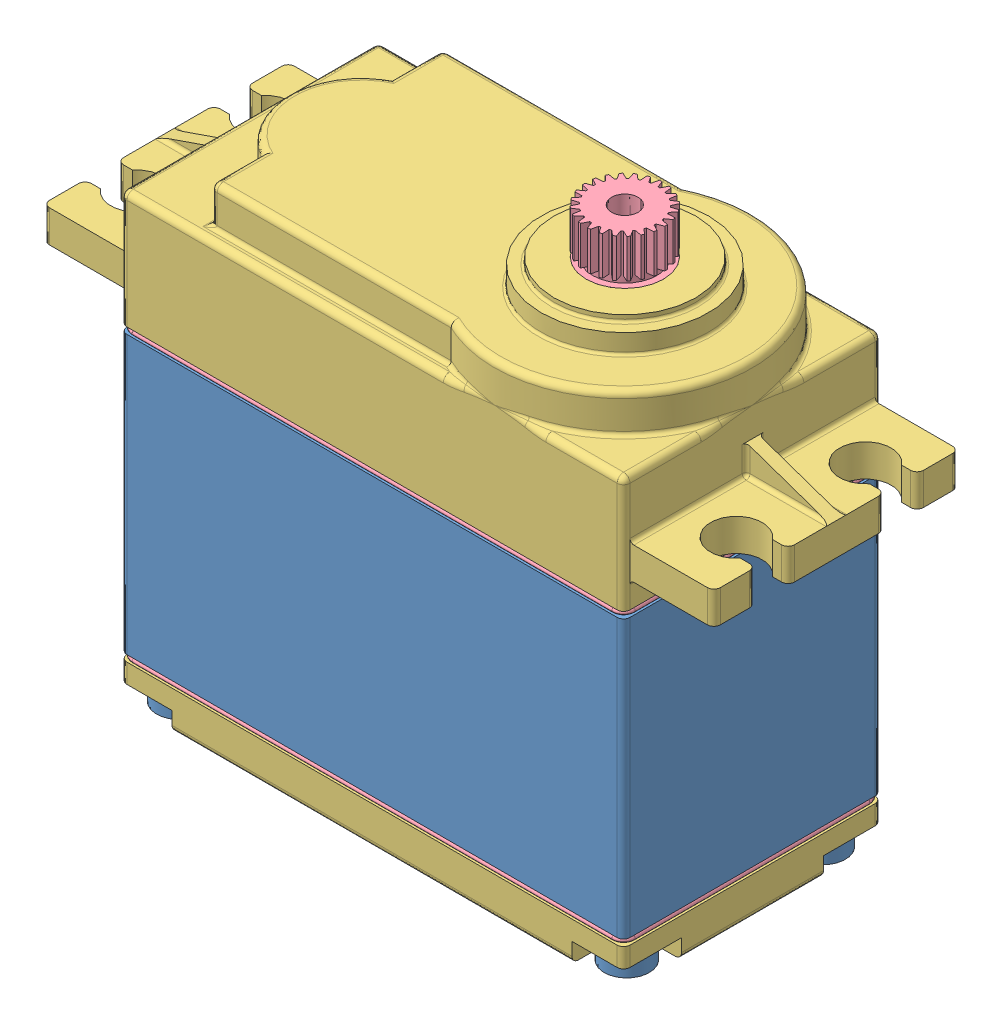
SolidWorks assembly РМ, configuration По умолчанию. Lengths in mm.
Overall size (52 43 23.81).
64 component instances, 28 part files, 82 mates.
Components (placement in the parent):
- Корпус-2: Корпус [По умолчанию] at origin size (39 28 20)
- Плата-1: Плата [По умолчанию] at (0 -10.5 0) x (-1 0 0) z (0 0 -1) size (37.4 1 18.4)
- Крышка-1: Крышка [По умолчанию] at (0 -13 0) x (-1 0 0) z (0 0 1) size (39 4 20)
- G1-1: G1 [Spur01] at (9.6 15.75 0) x (0.004766 0 0.999989) z (0 1 0) size (17.19 17.2 15.5)
- G2-1: G2 [Spur02] at (-1.2 16.75 0) x (-0.940242 0 0.340506) z (0 1 0) size (5.94 5.98 7)
- G3-1: G3 [G3] at (-1.2 19.25 0) x (0.340506 0 0.940242) z (0 1 0) size (13.18 13.2 2)
- G4-1: G4 [G4] at (-9.9 18.5 0) x (-0.495475 0 0.868622) z (0 -1 0) size (5.33 5.33 4)
- G5-1: G5 [G6] at (-9.9 12.5 0) x (0.495475 0 -0.868622) z (0 1 0) size (14.38 14.4 5.5)
- G6-1: G6 [G5] at (-1.2 12 0) x (0.105267 0 -0.994444) z (0 -1 0) size (4.1 4.1 2.5)
- G7-1: G7 [G7] at (-1.2 11.25 0) x (0.994444 0 0.105267) z (0 -1 0) size (14.99 15 1)
- G8-1: G8 [П8] at (-9.7 11.25 0) x (0.946769 0 0.321915) z (0 -1 0) size (2.9 3 1)
- Пласт2-1: Пласт2 [По умолчанию] at (9.6 16.5 0) x (0.004766 0 0.999989) z (0.999989 0 -0.004766) size (10 3.05 9.77)
- Пласт1-1: Пласт1 [По умолчанию] at (9.6 14.5 0) x (-0.004766 0 -0.999989) z (0.999989 0 -0.004766) size (7 1.5 9.77)
- Ось-1: Ось [По умолчанию] at (-1.2 15.75 0) x (0.961755 0 0.273911) z (0.273911 0 -0.961755) size (1.5 12.5 1.5)
- Ось1-1: Ось1 [По умолчанию] at (-9.9 18.75 0) x (0.831133 0 0.556074) z (-0.556074 0 0.831133) size (1.5 6.5 1.5)
- Подшипник_1-1: Подшипник_1 [По умолчанию] at (9.6 13.5 0) size (14.01 2 14.01)
  - Вн_кольцо-1: Вн_кольцо [По умолчанию] at origin size (7 2 7)
  - Нар_кольцо-2: Нар_кольцо [По умолчанию] x (0.605705 0 -0.795689) z (0.795689 0 0.605705) size (10 2 10)
  - Шарик-1: Шарик [По умолчанию] at (-3.9953 0 0.1946) size (1.5 1.5 1.5)
  - Шарик-2: Шарик [По умолчанию] at (-3.3466 0 -2.1909) x (0.809017 0 0.587785) z (-0.587785 0 0.809017) size (1.5 1.5 1.5)
  - Шарик-3: Шарик [По умолчанию] at (-1.4197 0 -3.7396) x (0.309017 0 0.951057) z (-0.951057 0 0.309017) size (1.5 1.5 1.5)
  - Шарик-4: Шарик [По умолчанию] at (1.0495 0 -3.8599) x (-0.309017 0 0.951057) z (-0.951057 0 -0.309017) size (1.5 1.5 1.5)
  - Шарик-5: Шарик [По умолчанию] at (3.1179 0 -2.5058) x (-0.809017 0 0.587785) z (-0.587785 0 -0.809017) size (1.5 1.5 1.5)
  - Шарик-6: Шарик [По умолчанию] at (3.9953 0 -0.1946) x (-1 0 0) z (0 0 -1) size (1.5 1.5 1.5)
  - Шарик-7: Шарик [По умолчанию] at (3.3466 0 2.1909) x (-0.809017 0 -0.587785) z (0.587785 0 -0.809017) size (1.5 1.5 1.5)
  - Шарик-8: Шарик [По умолчанию] at (1.4197 0 3.7396) x (-0.309017 0 -0.951057) z (0.951057 0 -0.309017) size (1.5 1.5 1.5)
  - Шарик-9: Шарик [По умолчанию] at (-1.0495 0 3.8599) x (0.309017 0 -0.951057) z (0.951057 0 0.309017) size (1.5 1.5 1.5)
  - Шарик-10: Шарик [По умолчанию] at (-3.1179 0 2.5058) x (0.809017 0 -0.587785) z (0.587785 0 0.809017) size (1.5 1.5 1.5)
- Винт-1: Винт [По умолчанию] at (17.35 0.5 7.6) x (0.946284 0 0.323336) z (0.323336 0 -0.946284) size (3.5 31 3.5)
- Упл_кольцо-1: Упл_кольцо [По умолчанию] at (17.35 -13.5 7.6) x (0.852696 0 0.522408) z (-0.522408 0 0.852696) size (3.2 0.5 3.2)
- Винт-2: Винт [По умолчанию] at (17.35 0 -7.6) x (0.966388 0 0.257088) z (0.257088 0 -0.966388) size (3.5 31 3.5) (suppressed, hidden)
- Упл_кольцо-2: Упл_кольцо [По умолчанию] at (17.35 -14 -7.6) size (3.2 0.5 3.2) (suppressed, hidden)
- Винт-3: Винт [По умолчанию] at (-17.35 0 -7.6) x (-0.966388 0 0.257088) z (0.257088 0 0.966388) size (3.5 31 3.5) (suppressed, hidden)
- Упл_кольцо-3: Упл_кольцо [По умолчанию] at (-17.35 -14 -7.6) x (-1 0 0) z (0 0 -1) size (3.2 0.5 3.2) (suppressed, hidden)
- Упл_кольцо-4: Упл_кольцо [По умолчанию] at (-17.35 -14 7.6) x (-1 0 0) z (0 0 -1) size (3.2 0.5 3.2) (suppressed, hidden)
- Винт-4: Винт [По умолчанию] at (-17.35 0 7.6) x (-0.966388 0 -0.257088) z (-0.257088 0 0.966388) size (3.5 31 3.5) (suppressed, hidden)
- Основание-1: Основание [По умолчанию] at (0 15 0) x (-1 0 0) z (0 0 -1) size (52 14 20.07)
- Подшипник_1-2: Подшипник_1 [По умолчанию] at (9.6 22 0) size (14.01 2 14.01)
  - Вн_кольцо-1: Вн_кольцо [По умолчанию] at origin size (7 2 7)
  - Нар_кольцо-2: Нар_кольцо [По умолчанию] x (0.605705 0 -0.795689) z (0.795689 0 0.605705) size (10 2 10)
  - Шарик-1: Шарик [По умолчанию] at (-3.9953 0 0.1946) size (1.5 1.5 1.5)
  - Шарик-2: Шарик [По умолчанию] at (-3.3466 0 -2.1909) x (0.809017 0 0.587785) z (-0.587785 0 0.809017) size (1.5 1.5 1.5)
  - Шарик-3: Шарик [По умолчанию] at (-1.4197 0 -3.7396) x (0.309017 0 0.951057) z (-0.951057 0 0.309017) size (1.5 1.5 1.5)
  - Шарик-4: Шарик [По умолчанию] at (1.0495 0 -3.8599) x (-0.309017 0 0.951057) z (-0.951057 0 -0.309017) size (1.5 1.5 1.5)
  - Шарик-5: Шарик [По умолчанию] at (3.1179 0 -2.5058) x (-0.809017 0 0.587785) z (-0.587785 0 -0.809017) size (1.5 1.5 1.5)
  - Шарик-6: Шарик [По умолчанию] at (3.9953 0 -0.1946) x (-1 0 0) z (0 0 -1) size (1.5 1.5 1.5)
  - Шарик-7: Шарик [По умолчанию] at (3.3466 0 2.1909) x (-0.809017 0 -0.587785) z (0.587785 0 -0.809017) size (1.5 1.5 1.5)
  - Шарик-8: Шарик [По умолчанию] at (1.4197 0 3.7396) x (-0.309017 0 -0.951057) z (0.951057 0 -0.309017) size (1.5 1.5 1.5)
  - Шарик-9: Шарик [По умолчанию] at (-1.0495 0 3.8599) x (0.309017 0 -0.951057) z (0.951057 0 0.309017) size (1.5 1.5 1.5)
  - Шарик-10: Шарик [По умолчанию] at (-3.1179 0 2.5058) x (0.809017 0 -0.587785) z (0.587785 0 0.809017) size (1.5 1.5 1.5)
- Прокл-1: Прокл [По умолчанию] at (0 -11.75 0) x (1 0 0) z (0 0 1) size (39 0.5 20)
- Прокл-2: Прокл [По умолчанию] at (0 10.25 0) size (39 0.5 20)
- Винт-8: Винт [По умолчанию] at (17.35 0.5 -7.6) x (0.946284 0 0.323336) z (0.323336 0 -0.946284) size (3.5 31 3.5)
- Упл_кольцо-5: Упл_кольцо [По умолчанию] at (17.35 -13.5 -7.6) x (0.852696 0 0.522408) z (-0.522408 0 0.852696) size (3.2 0.5 3.2)
- Винт-9: Винт [По умолчанию] at (-17.35 0.5 7.6) x (0.946284 0 0.323336) z (0.323336 0 -0.946284) size (3.5 31 3.5)
- Упл_кольцо-6: Упл_кольцо [По умолчанию] at (-17.35 -13.5 7.6) x (0.852696 0 0.522408) z (-0.522408 0 0.852696) size (3.2 0.5 3.2)
- Винт-10: Винт [По умолчанию] at (-17.35 0.5 -7.6) x (0.946284 0 0.323336) z (0.323336 0 -0.946284) size (3.5 31 3.5)
- Упл_кольцо-7: Упл_кольцо [По умолчанию] at (-17.35 -13.5 -7.6) x (0.852696 0 0.522408) z (-0.522408 0 0.852696) size (3.2 0.5 3.2)
- Штырь-1: Штырь [По умолчанию] at (16.0999 17 -0.031) x (-0.26515 0 -0.964207) z (0.964207 0 -0.26515) size (2 7 2)
- Дв_корп-1: Дв_корп [По умолчанию] at (-9.7 0 0) size (17.2 18 17.2)
- Дв_вал-1: Дв_вал [По умолчанию] at (-9.7 7 0) size (1 10 1)
- Дв_крышка-1: Дв_крышка [По умолчанию] at (-9.7 -9.5 0) x (-0.837169 0 -0.546944) z (-0.546944 0 0.837169) size (17.2 2 17.2)
- Птнц_корп-1: Птнц_корп [По умолчанию] at (9.6 5 0) size (10 4 10)
- Птнц_вал-1: Птнц_вал [По умолчанию] at (9.6 12.5 0) x (-0.004766 0 -0.999989) z (0.999989 0 -0.004766) size (4 11 4)
Mates (geometry in assembly coordinates):
- Совпадение7: coincident anti-aligned: plane of Корпус-2 through (0 -10 -32.5618) normal (0 -1 0); plane of Плата-1 through (32.5618 -10 0) normal (0 1 0)
- Совпадение8: coincident anti-aligned: plane of Корпус-2 through (19.5 -11 -9.2) normal (0 0 1); plane of Плата-1 through (32.5618 -10 -9.2) normal (0 0 -1)
- Совпадение9: coincident anti-aligned: plane of Корпус-2 through (18.7 -11 -10) normal (-1 0 0); plane of Плата-1 through (18.7 -10 0) normal (1 0 0)
- Совпадение10: coincident anti-aligned: plane of Корпус-2 through (18.7 -11 -9.2) normal (0 -1 0); plane of Крышка-1 through (19.5 -11 -10) normal (0 1 0)
- Совпадение12: coincident anti-aligned: plane of Корпус-2 through (19.5 -11 -9.2) normal (0 0 1); plane of Крышка-1 through (-18.7 -12 -9.2) normal (0 0 -1)
- Совпадение13: coincident anti-aligned: plane of Корпус-2 through (-18.7 -11 -10) normal (1 0 0); plane of Крышка-1 through (-18.7 -12 9.2) normal (-1 0 0)
- Концентричный1: concentric aligned: cylinder of G2-1 through (-1.2 18.25 0) axis (0 1 0) radius 2.5; cylinder of G3-1 through (-1.2 11.1789 0) axis (0 1 0) radius 2.5
- Совпадение14: coincident anti-aligned: plane of G2-1 through (-1.2 18.25 0) normal (0 1 0); plane of G3-1 through (5.0056 18.25 -2.2473) normal (0 -1 0)
- Концентричный2: concentric anti-aligned: cylinder of G4-1 through (-9.9 17.5 0) axis (0 -1 0) radius 2.4; cylinder of G5-1 through (-9.9 9.7118 0) axis (0 1 0) radius 2.4
- Совпадение15: coincident anti-aligned: plane of G4-1 through (-9.9 17.5 0) normal (0 -1 0); plane of G5-1 through (-9.9 17.5 0) normal (0 1 0)
- Концентричный3: concentric aligned: cylinder of G6-1 through (-1.2 11.75 0) axis (0 -1 0) radius 1.75; cylinder of G7-1 through (-1.2 16.6997 0) axis (0 -1 0) radius 1.75
- Совпадение16: coincident anti-aligned: plane of G6-1 through (-7.904 11.75 -0.7097) normal (0 -1 0); plane of G7-1 through (-1.9895 11.75 7.4583) normal (0 1 0)
- Концентричный4: concentric anti-aligned: cylinder of Пласт2-1 through (9.6 8.4289 0) axis (0 1 0) radius 2.5; cylinder of Пласт1-1 through (9.6 16 0) axis (0 -1 0) radius 2.5
- Концентричный5: concentric anti-aligned: cylinder of Пласт2-1 through (4.6001 14.5 0.0238) axis (0 1 0) radius 1.5; cylinder of Пласт1-1 through (4.6001 15.5 0.0238) axis (0 -1 0) radius 1.5
- Совпадение17: coincident anti-aligned: plane of Пласт2-1 through (9.66 15.5 -11.0188) normal (0 -1 0); plane of Пласт1-1 through (9.6282 15.5 11.1805) normal (0 1 0)
- Концентричный6: concentric aligned: cylinder of G1-1 through (9.6 19 0) axis (0 -1 0) radius 3; cylinder of Пласт2-1 through (9.6 17.5 0) axis (0 -1 0) radius 3
- Совпадение18: coincident aligned: plane of G1-1; plane of Пласт2-1
- Совпадение19: coincident anti-aligned: plane of G1-1 through (9.6 16.5 0) normal (0 -1 0); plane of Пласт2-1 through (9.5216 16.5 -11.1803) normal (0 1 0)
- Концентричный7: concentric anti-aligned: cylinder of G6-1 through (-1.2 15.3713 0) axis (0 -1 0) radius 0.75; cylinder of Ось-1 through (-1.2 9.5 0) axis (0 1 0) radius 0.75
- Совпадение21: coincident aligned: plane of G7-1 through (-1.2 11.25 0) normal (0 -1 0); plane of G8-1 through (-9.7 11.25 0) normal (0 -1 0)
- Совпадение23: coincident: line of G7-1 through (-1.2 -43.75 0) axis (0 1 0); plane of assembly
- Совпадение25: coincident anti-aligned: plane of Корпус-2 through (-1.2 9.5 0) normal (0 1 0); plane of Ось-1 through (-1.2 9.5 0) normal (0 -1 0)
- Совпадение26: coincident anti-aligned: plane of Корпус-2 through (-30.4875 10.75 0) normal (0 1 0); plane of G6-1 through (-1.2 10.75 0) normal (0 -1 0)
- Концентричный8: concentric aligned: cylinder of Корпус-2 through (-1.2 9.5 0) axis (0 1 0) radius 0.75; cylinder of Ось-1 through (-1.2 9.5 0) axis (0 1 0) radius 0.75
- Концентричный9: concentric aligned: cylinder of G4-1 through (-9.9 18.5 0) axis (0 -1 0) radius 0.75; cylinder of Ось1-1 through (-9.9 22 0) axis (0 -1 0) radius 0.75
- Совпадение32: coincident aligned: plane of G6-1; plane of G7-1
- Совпадение33: coincident anti-aligned: plane of G4-1; plane of G5-1
- Концентричный10: concentric aligned: cylinder of G2-1 through (-1.2 11.1287 0) axis (0 1 0) radius 0.75; cylinder of Ось-1 through (-1.2 9.5 0) axis (0 1 0) radius 0.75
- Совпадение34: coincident anti-aligned: plane of G2-1 through (-0.1785 13.25 2.8207) normal (0 -1 0); plane of G6-1 through (0.8883 13.25 0.2211) normal (0 1 0)
- Совпадение35: coincident anti-aligned: plane of G2-1; plane of G3-1
- Концентричный11: concentric aligned: cylinder of Корпус-2 through (9.6 14.5 0) axis (0 -1 0) radius 3; cylinder of Подшипник_1-1/Вн_кольцо-1 through (9.6 14.5 0) axis (0 -1 0) radius 3
- Совпадение36: coincident anti-aligned: plane of Корпус-2 through (9.6 12.5 0) normal (0 1 0); plane of Подшипник_1-1/Вн_кольцо-1 through (9.6 12.5 0) normal (0 -1 0)
- Концентричный13: concentric aligned: cylinder of G1-1 through (9.6 16.5 0) axis (0 -1 0) radius 5; cylinder of Подшипник_1-1/Нар_кольцо-2 through (9.6 14.5 0) axis (0 -1 0) radius 5
- Совпадение39: coincident anti-aligned: plane of Пласт1-1 through (9.6282 14.5 11.1805) normal (0 -1 0); plane of Подшипник_1-1/Нар_кольцо-2 through (9.6 14.5 0) normal (0 1 0)
- Сопряжения редуктора5: gear = 5.2 : 16.4 mm: circle of G1-1; circle of G2-1
- Совпадение40: coincident anti-aligned: plane of Корпус-2 through (-14.4414 15.5 0) normal (0 1 0); plane of Ось1-1 through (-9.9 15.5 0) normal (0 -1 0)
- Концентричный16: concentric anti-aligned: cylinder of Корпус-2 through (-9.9 15.5 0) axis (0 1 0) radius 0.75; cylinder of Ось1-1 through (-9.9 22 0) axis (0 -1 0) radius 0.75
- Совпадение41: coincident anti-aligned: plane of Корпус-2 through (-17.7642 16.5 0) normal (0 1 0); plane of G4-1 through (-9.9 16.5 0) normal (0 -1 0)
- Концентричный19: concentric aligned: cylinder of Корпус-2 through (-9.7 11.9142 0) axis (0 -1 0) radius 0.5; circle of G8-1
- Сопряжения редуктора6: gear = 2.5 : 14.5 mm: circle of G7-1; circle of G8-1
- Сопряжения редуктора7: gear = 3.6 : 13.8 mm: circle of G5-1; circle of G6-1
- Сопряжения редуктора8: gear = 4.8 : 12.6 mm: circle of G3-1; circle of G4-1
- Концентричный20: concentric aligned: cylinder of Крышка-1 through (17.35 -13 7.6) axis (0 -1 0) radius 1.6; cylinder of Упл_кольцо-1 through (17.35 -13 7.6) axis (0 -1 0) radius 1.6
- Совпадение43: coincident anti-aligned: plane of Винт-1 through (17.35 -13.5 7.6) normal (0 1 0); plane of Упл_кольцо-1 through (17.35 -13.5 7.6) normal (0 -1 0)
- Концентричный24: concentric aligned: cylinder of Крышка-1 through (17.35 -8.1716 7.6) axis (0 -1 0) radius 1; cylinder of Винт-1 through (17.35 -15 7.6) axis (0 -1 0) radius 0.8
- Совпадение48: coincident anti-aligned: plane of Основание-1 through (0 15 0) normal (0 0 -1); plane of assembly through (0 0 0) normal (0 0 1)
- Концентричный25: concentric aligned: cylinder of Основание-1 through (9.6 23 0) axis (0 -1 0) radius 5; cylinder of Подшипник_1-2/Нар_кольцо-2 through (9.6 23 0) axis (0 -1 0) radius 5
- Совпадение49: coincident anti-aligned: plane of Основание-1 through (9.6 23 0) normal (0 -1 0); plane of Подшипник_1-2/Нар_кольцо-2 through (9.6 23 0) normal (0 1 0)
- Совпадение50: coincident anti-aligned: plane of Основание-1 through (0 15 0) normal (-1 0 0); plane of assembly through (0 0 0) normal (1 0 0)
- Касательность1: tangent: plane of Корпус-2 through (19.5 -11.5 -10) normal (0 -1 0); face of Прокл-1
- Касательность2: tangent: plane of Крышка-1 through (18.7 -12 -9.2) normal (1 0 0); face of Прокл-1
- Касательность3: tangent: plane of Крышка-1 through (-18.7 -12 -9.2) normal (0 0 -1); face of Прокл-1
- Совпадение51: coincident anti-aligned: plane of Корпус-2 through (19.5 11.5 -10) normal (0 1 0); plane of Основание-1 through (-18.7 11.5 9.2) normal (0 -1 0)
- Совпадение52: coincident aligned: plane of Корпус-2 through (0 0 0) normal (0 0 1); plane of Прокл-2 through (0 10.25 0) normal (0 0 1)
- Совпадение53: coincident aligned: plane of Корпус-2 through (0 0 0) normal (1 0 0); plane of Прокл-2 through (0 10.25 0) normal (1 0 0)
- Расстояние1: distance = 0.25 mm aligned: plane of Корпус-2 through (-34.2325 10 0) normal (0 1 0); plane of Прокл-2 through (0 10.25 0) normal (0 1 0)
- Совпадение58: coincident anti-aligned: plane of Крышка-1 through (17.35 -13 7.6) normal (0 -1 0); plane of Упл_кольцо-1 through (17.35 -13 7.6) normal (0 1 0)
- Совпадение59: coincident anti-aligned: plane of Винт-8 through (17.35 -13.5 -7.6) normal (0 1 0); plane of Упл_кольцо-5 through (17.35 -13.5 -7.6) normal (0 -1 0)
- Концентричный29: concentric aligned: cylinder of Крышка-1 through (17.35 -13 -7.6) axis (0 -1 0) radius 1.6; cylinder of Упл_кольцо-5 through (17.35 -13 -7.6) axis (0 -1 0) radius 1.6
- Концентричный30: concentric aligned: cylinder of Крышка-1 through (17.35 -8.1716 -7.6) axis (0 -1 0) radius 1; cylinder of Винт-8 through (17.35 -15 -7.6) axis (0 -1 0) radius 0.8
- Совпадение60: coincident anti-aligned: plane of Крышка-1 through (17.35 -13 -7.6) normal (0 -1 0); plane of Упл_кольцо-5 through (17.35 -13 -7.6) normal (0 1 0)
- Совпадение61: coincident anti-aligned: plane of Винт-9 through (-17.35 -13.5 7.6) normal (0 1 0); plane of Упл_кольцо-6 through (-17.35 -13.5 7.6) normal (0 -1 0)
- Концентричный31: concentric aligned: cylinder of Крышка-1 through (-17.35 -13 7.6) axis (0 -1 0) radius 1.6; cylinder of Упл_кольцо-6 through (-17.35 -13 7.6) axis (0 -1 0) radius 1.6
- Концентричный32: concentric aligned: cylinder of Крышка-1 through (-17.35 -8.1716 7.6) axis (0 -1 0) radius 1; cylinder of Винт-9 through (-17.35 -15 7.6) axis (0 -1 0) radius 0.8
- Совпадение62: coincident anti-aligned: plane of Крышка-1 through (-17.35 -13 7.6) normal (0 -1 0); plane of Упл_кольцо-6 through (-17.35 -13 7.6) normal (0 1 0)
- Совпадение63: coincident anti-aligned: plane of Винт-10 through (-17.35 -13.5 -7.6) normal (0 1 0); plane of Упл_кольцо-7 through (-17.35 -13.5 -7.6) normal (0 -1 0)
- Концентричный33: concentric aligned: cylinder of Крышка-1 through (-17.35 -13 -7.6) axis (0 -1 0) radius 1.6; cylinder of Упл_кольцо-7 through (-17.35 -13 -7.6) axis (0 -1 0) radius 1.6
- Концентричный34: concentric aligned: cylinder of Крышка-1 through (-17.35 -8.1716 -7.6) axis (0 -1 0) radius 1; cylinder of Винт-10 through (-17.35 -15 -7.6) axis (0 -1 0) radius 0.8
- Совпадение64: coincident anti-aligned: plane of Крышка-1 through (-17.35 -13 -7.6) normal (0 -1 0); plane of Упл_кольцо-7 through (-17.35 -13 -7.6) normal (0 1 0)
- Концентричный35: concentric anti-aligned: cylinder of G1-1 through (16.0999 9.6716 -0.031) axis (0 1 0) radius 1; cylinder of Штырь-1 through (16.0999 20.5 -0.031) axis (0 -1 0) radius 1
- Совпадение65: coincident aligned: plane of G1-1 through (18.1999 13.5 -0.041) normal (0 -1 0); plane of Штырь-1 through (16.0999 13.5 -0.031) normal (0 -1 0)
- Совпадение66: coincident anti-aligned: plane of Корпус-2 through (0 9 -33.3273) normal (0 -1 0); plane of Дв_корп-1 through (-10.2 9 0) normal (0 1 0)
- Концентричный36: concentric aligned: cylinder of Дв_корп-1 through (-9.7 -16.8719 0) axis (0 -1 0) radius 0.5; cylinder of Дв_вал-1 through (-9.7 12 0) axis (0 -1 0) radius 0.5
- Расстояние2: distance = 3 mm aligned: plane of Дв_вал-1 through (-9.7 12 0) normal (0 1 0); plane of Дв_корп-1 through (-10.2 9 0) normal (0 1 0)
- Концентричный37: concentric aligned: cylinder of G8-1 through (-9.7 13.1642 0) axis (0 -1 0) radius 0.5; cylinder of Дв_вал-1 through (-9.7 12 0) axis (0 -1 0) radius 0.5
- Концентричный38: concentric anti-aligned: cylinder of Дв_корп-1 through (-9.7 -16.8719 0) axis (0 -1 0) radius 7.6; cylinder of Дв_крышка-1 through (-9.7 -9 0) axis (0 1 0) radius 7.6
- Совпадение67: coincident anti-aligned: plane of Плата-1 through (32.5618 -10 0) normal (0 1 0); plane of Дв_крышка-1 through (-9.7 -10 0) normal (0 -1 0)
- Концентричный41: concentric anti-aligned: cylinder of Птнц_корп-1 through (9.6 7 0) axis (0 1 0) radius 2; cylinder of Птнц_вал-1 through (9.6 18 0) axis (0 -1 0) radius 2
- Концентричный42: concentric anti-aligned: cylinder of Корпус-2 through (9.6 3.3431 0) axis (0 1 0) radius 2; cylinder of Птнц_вал-1 through (9.6 18 0) axis (0 -1 0) radius 2
- Совпадение71: coincident anti-aligned: plane of Корпус-2 through (0 9 -33.3273) normal (0 -1 0); plane of Птнц_корп-1 through (4.6 9 0) normal (0 1 0)
- Совпадение72: coincident anti-aligned: plane of Пласт1-1 through (8.6269 10.0279 5.6461) normal (0.999989 0 -0.004766); plane of Птнц_вал-1 through (8.6095 16 2.0057) normal (-0.999989 0 0.004766)
- Совпадение73: coincident anti-aligned: plane of Птнц_корп-1 through (7.6 7 0) normal (0 1 0); plane of Птнц_вал-1 through (9.6 7 0) normal (0 -1 0)
